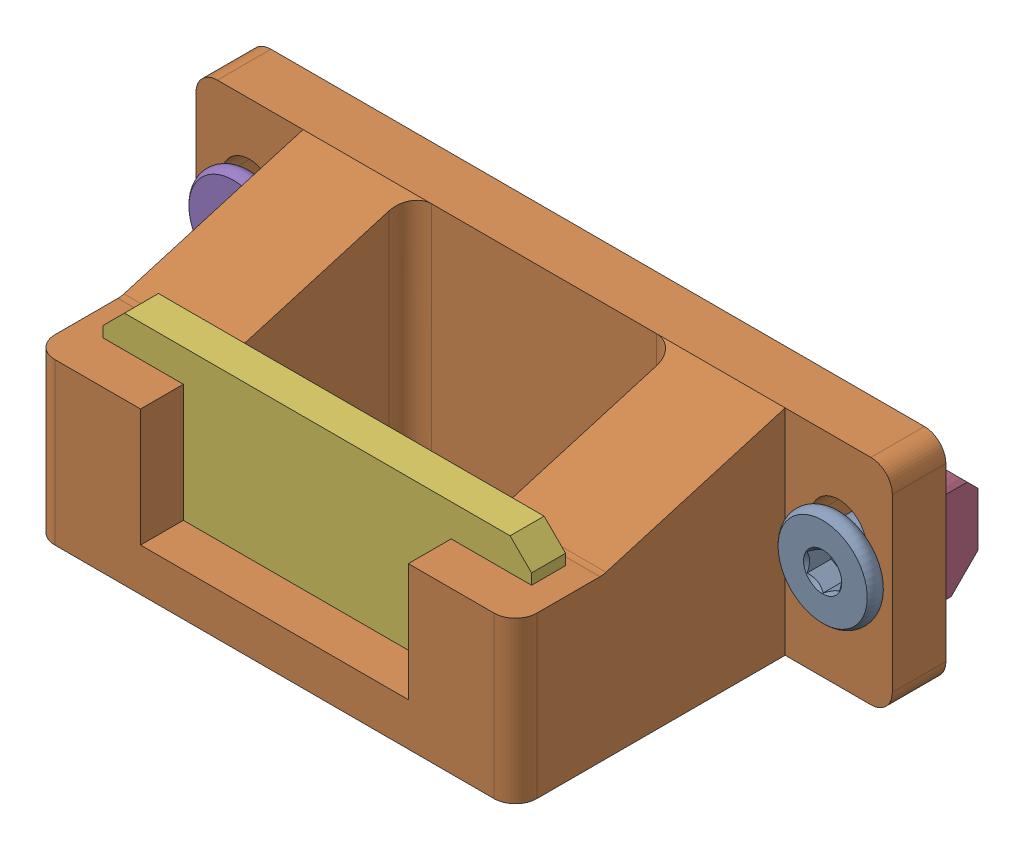
SolidWorks assembly extruder_wiper_assembly_2, configuration Default. Lengths in mm.
Overall size (65 20 35.18).
6 component instances, 4 part files, 0 mates.
Components (placement in the parent):
- m5_low_profile_screw_template_M5 x 10-1: m5_low_profile_screw_template_M5 x 10 [Default] at (-67.018 10 -35.175) x (0 0 -1) z (1 0 0) size (11.62 9 9)
- ooze_wiper_v1-1: ooze_wiper_v1 [Default] at (-107.018 0 -30.175) size (65 20 30.18)
- m5_locking_t_nut_20x20_generic-1: m5_locking_t_nut_20x20_generic [Default] at (-119.018 10 -35.175) x (0 -1 0) z (-1 0 0) size (10 4.5 6)
- m5_locking_t_nut_20x20_generic-2: m5_locking_t_nut_20x20_generic [Default] at (-64.018 10 -35.175) x (0 -1 0) z (-1 0 0) size (10 4.5 6)
- m5_low_profile_screw_template_M5 x 10-2: m5_low_profile_screw_template_M5 x 10 [Default] at (-122.018 10 -35.175) x (0 0 -1) z (1 0 0) size (11.62 9 9)
- silicone_wiper-1: silicone_wiper [Default] at (-114.518 3 -7.175) x (1 0 0) z (0 -1 0) size (40 3.17 15)
